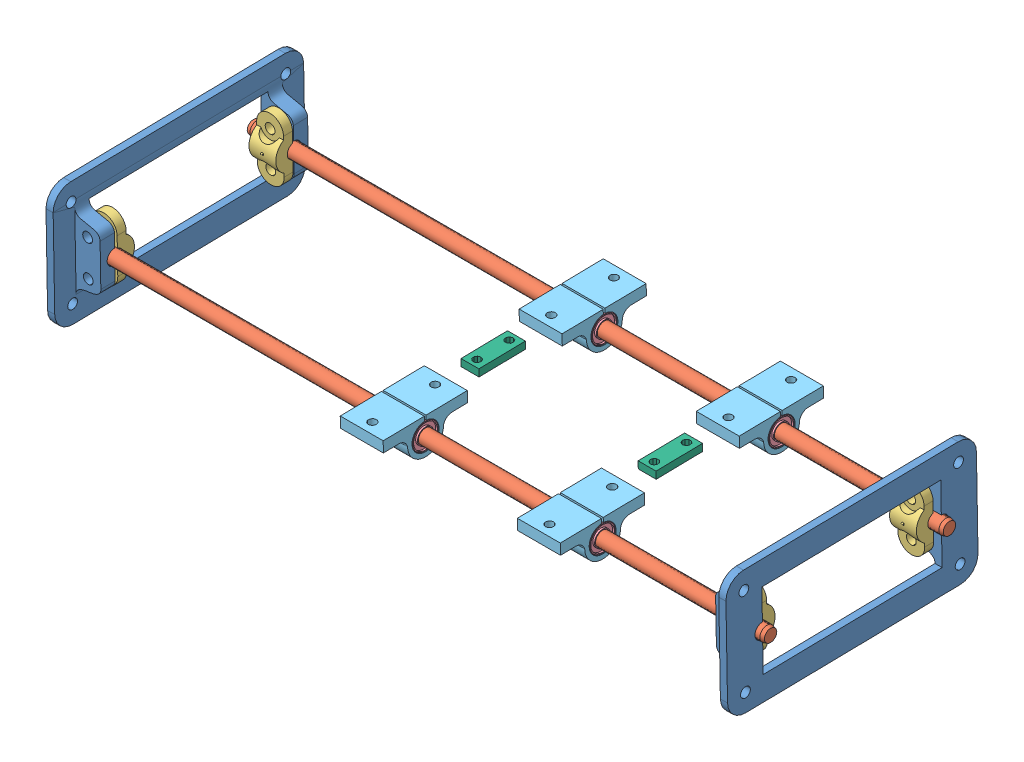
SolidWorks assembly MS1 - SubAssembly B - Yaxis, configuration Default. Lengths in mm.
Overall size (389 72.16 147.33).
18 component instances, 6 part files, 45 mates.
Components (placement in the parent):
- Y Rod Mount-1: Y Rod Mount [Default] at (380 175.2275 237.1388) x (-1 0 0) z (0 0.017689 -0.999844) size (18.11 69.69 140)
- Y Rod Mount-2: Y Rod Mount [Default] at (0 172.751 377.1169) x (1 0 0) z (0 -0.017689 0.999844) size (18.11 69.69 140)
- Steel Rod-3: Steel Rod [Default] at (190 173.1048 357.12) size (389 8 8)
- Steel Rod-4: Steel Rod [Default] at (190 174.8737 257.1356) size (389 8 8)
- Z Rod Clamp-1: Z Rod Clamp [Default] at (369 174.856 258.1355) x (0 0.999844 0.017689) z (1 0 0) size (35 10 15)
- Z Rod Clamp-2: Z Rod Clamp [Default] at (11 174.856 258.1355) x (0 0.999844 0.017689) z (1 0 0) size (35 10 15)
- Z Rod Clamp-3: Z Rod Clamp [Default] at (11 173.1225 356.1202) x (0 -0.999844 -0.017689) z (1 0 0) size (35 10 15)
- Z Rod Clamp-4: Z Rod Clamp [Default] at (369 173.1225 356.1202) x (0 -0.999844 -0.017689) z (1 0 0) size (35 10 15)
- LM8UU Bearing-1: LM8UU Bearing [Default] at (278.6557 173.1048 357.12) size (24 15 15)
- LM8UU Bearing-2: LM8UU Bearing [Default] at (179.6557 173.1048 357.12) size (24 15 15)
- LM8UU Bearing-3: LM8UU Bearing [Default] at (278.6557 174.8737 257.1356) x (1 0 0) z (0 0.453084 0.891468) size (24 15 15)
- LM8UU Bearing-4: LM8UU Bearing [Default] at (179.6557 174.8737 257.1356) size (24 15 15)
- LM8UU Bearing Holder-1: LM8UU Bearing Holder [Default] at (266.6557 183.542 333.7824) x (0 -0.017689 0.999844) z (0 0.999844 0.017689) size (47 24 20.05)
- LM8UU Bearing Holder-2: LM8UU Bearing Holder [Default] at (167.6557 183.542 333.7824) x (0 -0.017689 0.999844) z (0 0.999844 0.017689) size (47 24 20.05)
- LM8UU Bearing Holder-3: LM8UU Bearing Holder [Default] at (266.6557 185.3109 233.798) x (0 -0.017689 0.999844) z (0 0.999844 0.017689) size (47 24 20.05)
- LM8UU Bearing Holder-4: LM8UU Bearing Holder [Default] at (167.6557 185.3109 233.798) x (0 -0.017689 0.999844) z (0 0.999844 0.017689) size (47 24 20.05)
- Y Belt Clamp-1: Y Belt Clamp [Default] at (273.6557 180.2413 294.2178) x (0 -0.017689 0.999844) z (0 0.999844 0.017689) size (26 10 4)
- Y Belt Clamp-2: Y Belt Clamp [Default] at (174.6557 183.7808 320.2845) x (0 0.017689 -0.999844) z (0 -0.999844 -0.017689) size (26 10 4)
Mates (geometry in assembly coordinates):
- Coincident1: coincident anti-aligned: plane of Y Rod Mount-2 through (0 210.0682 237.7552) normal (-1 0 0); plane of assembly through (0 0 0) normal (1 0 0)
- Coincident2: coincident aligned: plane of Y Rod Mount-1 through (380 207.5917 377.7333) normal (1 0 0); plane of assembly through (380 0 0) normal (1 0 0)
- Distance1: distance = 0 mm aligned: plane of Y Rod Mount-2 through (11.0136 156.2553 376.825) normal (0 -0.017689 0.999844); plane of Y Rod Mount-1 through (368.9864 156.2553 376.825) normal (0 -0.017689 0.999844)
- Distance2: distance = 0 mm aligned: plane of Y Rod Mount-2 through (0 210.0682 237.7552) normal (0 0.999844 0.017689); plane of Y Rod Mount-1 through (380 207.5917 377.7333) normal (0 0.999844 0.017689)
- Concentric3: concentric aligned: cylinder of Y Rod Mount-2 through (18.1149 174.8737 257.1356) axis (-1 0 0) radius 4.2788; cylinder of Steel Rod-4 through (384.5 174.8737 257.1356) axis (-1 0 0) radius 4
- Concentric4: concentric aligned: cylinder of Y Rod Mount-2 through (18.1149 173.1048 357.12) axis (-1 0 0) radius 4.2788; cylinder of Steel Rod-3 through (384.5 173.1048 357.12) axis (-1 0 0) radius 4
- Distance3: distance = 4.5 mm aligned: plane of Steel Rod-3 through (-4.5 173.1048 357.12) normal (-1 0 0); plane of Y Rod Mount-2 through (0 210.0682 237.7552) normal (-1 0 0)
- Distance4: distance = 4.5 mm aligned: plane of Steel Rod-4 through (-4.5 174.8737 257.1356) normal (-1 0 0); plane of Y Rod Mount-2 through (0 210.0682 237.7552) normal (-1 0 0)
- Concentric5: concentric anti-aligned: cylinder of Steel Rod-4 through (384.5 174.8737 257.1356) axis (-1 0 0) radius 4; cylinder of Z Rod Clamp-1 through (361.5 174.8737 257.1356) axis (1 0 0) radius 4.1
- Concentric6: concentric anti-aligned: cylinder of Steel Rod-4 through (384.5 174.8737 257.1356) axis (-1 0 0) radius 4; cylinder of Z Rod Clamp-2 through (3.5 174.8737 257.1356) axis (1 0 0) radius 4.1
- Concentric7: concentric anti-aligned: cylinder of Steel Rod-3 through (384.5 173.1048 357.12) axis (-1 0 0) radius 4; cylinder of Z Rod Clamp-3 through (3.5 173.1048 357.12) axis (1 0 0) radius 4.1
- Concentric8: concentric anti-aligned: cylinder of Steel Rod-3 through (384.5 173.1048 357.12) axis (-1 0 0) radius 4; cylinder of Z Rod Clamp-4 through (361.5 173.1048 357.12) axis (1 0 0) radius 4.1
- Parallel2: parallel anti-aligned: plane of Y Rod Mount-2 through (18.1149 173.1048 357.12) normal (0 0.017689 -0.999844); plane of Z Rod Clamp-3 through (11 173.1225 356.1202) normal (0 -0.017689 0.999844)
- Distance6: distance = 0.5 mm aligned: plane of Y Rod Mount-2 through (18 186.992 237.3469) normal (1 0 0); plane of Z Rod Clamp-3 through (18.5 173.2905 346.6217) normal (1 0 0)
- Parallel5: parallel anti-aligned: plane of Y Rod Mount-2 through (18.1149 174.8737 257.1356) normal (0 -0.017689 0.999844); plane of Z Rod Clamp-2 through (11 174.856 258.1355) normal (0 0.017689 -0.999844)
- Distance7: distance = 0.5 mm aligned: plane of Z Rod Clamp-2 through (18.5 174.688 267.634) normal (1 0 0); plane of Y Rod Mount-2 through (18 186.992 237.3469) normal (1 0 0)
- Parallel6: parallel anti-aligned: plane of Y Rod Mount-1 through (361.8851 174.8737 257.1356) normal (0 -0.017689 0.999844); plane of Z Rod Clamp-1 through (369 174.856 258.1355) normal (0 0.017689 -0.999844)
- Distance9: distance = 0.5 mm aligned: plane of Z Rod Clamp-1 through (361.5 174.688 267.634) normal (-1 0 0); plane of Y Rod Mount-1 through (362 184.5155 377.325) normal (-1 0 0)
- Parallel7: parallel anti-aligned: plane of Y Rod Mount-1 through (361.8851 173.1048 357.12) normal (0 0.017689 -0.999844); plane of Z Rod Clamp-4 through (369 173.1225 356.1202) normal (0 -0.017689 0.999844)
- Distance10: distance = 0.5 mm aligned: plane of Z Rod Clamp-4 through (361.5 173.2905 346.6217) normal (-1 0 0); plane of Y Rod Mount-1 through (362 184.5155 377.325) normal (-1 0 0)
- Concentric11: concentric anti-aligned: cylinder of Steel Rod-4 through (384.5 174.8737 257.1356) axis (-1 0 0) radius 4; cylinder of LM8UU Bearing Holder-4 through (167.6557 174.8737 257.1356) axis (1 0 0) radius 7.55
- Parallel8: parallel aligned: plane of Y Rod Mount-2 through (0 210.0682 237.7552) normal (0 0.999844 0.017689); plane of LM8UU Bearing Holder-4 through (167.6557 185.3109 233.798) normal (0 0.999844 0.017689)
- Concentric12: concentric aligned: cylinder of Steel Rod-4 through (384.5 174.8737 257.1356) axis (-1 0 0) radius 4; cylinder of LM8UU Bearing-4 through (133.9662 174.8737 257.1356) axis (-1 0 0) radius 4
- Coincident18: coincident aligned: plane of LM8UU Bearing-4 through (191.6557 174.8737 257.1356) normal (1 0 0); plane of LM8UU Bearing Holder-4 through (191.6557 173.5638 272.0962) normal (1 0 0)
- Concentric13: concentric aligned: cylinder of Steel Rod-4 through (384.5 174.8737 257.1356) axis (-1 0 0) radius 4; cylinder of LM8UU Bearing-3 through (232.9662 174.8737 257.1356) axis (-1 0 0) radius 4
- Concentric14: concentric anti-aligned: cylinder of LM8UU Bearing-3 through (232.9662 174.8737 257.1356) axis (-1 0 0) radius 7.5; cylinder of LM8UU Bearing Holder-3 through (266.6557 174.8737 257.1356) axis (1 0 0) radius 7.55
- Coincident19: coincident aligned: plane of LM8UU Bearing Holder-3 through (266.6557 185.3109 233.798) normal (0 0.999844 0.017689); plane of LM8UU Bearing Holder-4 through (167.6557 185.3109 233.798) normal (0 0.999844 0.017689)
- Coincident20: coincident aligned: plane of LM8UU Bearing-3 through (290.6557 174.8737 257.1356) normal (1 0 0); plane of LM8UU Bearing Holder-3 through (290.6557 173.5638 272.0962) normal (1 0 0)
- Concentric15: concentric aligned: cylinder of Steel Rod-3 through (384.5 173.1048 357.12) axis (-1 0 0) radius 4; cylinder of LM8UU Bearing-2 through (133.9662 173.1048 357.12) axis (-1 0 0) radius 4
- Concentric16: concentric anti-aligned: cylinder of LM8UU Bearing-2 through (133.9662 173.1048 357.12) axis (-1 0 0) radius 7.5; cylinder of LM8UU Bearing Holder-2 through (167.6557 173.1048 357.12) axis (1 0 0) radius 7.55
- Coincident21: coincident aligned: plane of LM8UU Bearing Holder-2 through (167.6557 183.542 333.7824) normal (0 0.999844 0.017689); plane of LM8UU Bearing Holder-4 through (167.6557 185.3109 233.798) normal (0 0.999844 0.017689)
- Coincident22: coincident aligned: plane of LM8UU Bearing-2 through (191.6557 173.1048 357.12) normal (1 0 0); plane of LM8UU Bearing Holder-2 through (191.6557 171.7949 372.0806) normal (1 0 0)
- Concentric17: concentric aligned: cylinder of Steel Rod-3 through (384.5 173.1048 357.12) axis (-1 0 0) radius 4; cylinder of LM8UU Bearing-1 through (232.9662 173.1048 357.12) axis (-1 0 0) radius 4
- Concentric18: concentric anti-aligned: cylinder of LM8UU Bearing-1 through (232.9662 173.1048 357.12) axis (-1 0 0) radius 7.5; cylinder of LM8UU Bearing Holder-1 through (266.6557 173.1048 357.12) axis (1 0 0) radius 7.55
- Coincident23: coincident aligned: plane of LM8UU Bearing Holder-1 through (266.6557 183.542 333.7824) normal (0 0.999844 0.017689); plane of LM8UU Bearing Holder-2 through (167.6557 183.542 333.7824) normal (0 0.999844 0.017689)
- Coincident24: coincident aligned: plane of LM8UU Bearing-1 through (290.6557 173.1048 357.12) normal (1 0 0); plane of LM8UU Bearing Holder-1 through (290.6557 171.7949 372.0806) normal (1 0 0)
- Coincident25: coincident aligned: plane of LM8UU Bearing Holder-1 through (290.6557 171.7949 372.0806) normal (1 0 0); plane of LM8UU Bearing Holder-3 through (290.6557 173.5638 272.0962) normal (1 0 0)
- Coincident26: coincident aligned: plane of LM8UU Bearing Holder-2 through (191.6557 171.7949 372.0806) normal (1 0 0); plane of LM8UU Bearing Holder-4 through (191.6557 173.5638 272.0962) normal (1 0 0)
- Distance11: distance = 75 mm anti-aligned: plane of LM8UU Bearing Holder-2 through (191.6557 171.7949 372.0806) normal (1 0 0); plane of LM8UU Bearing Holder-1 through (266.6557 171.7949 372.0806) normal (-1 0 0)
- Coincident28: coincident aligned: plane of LM8UU Bearing Holder-1 through (266.6557 183.542 333.7824) normal (0 0.999844 0.017689); plane of Y Belt Clamp-1 through (273.6557 184.2407 294.2885) normal (0 0.999844 0.017689)
- Distance14: distance = 13.5 mm anti-aligned: plane of LM8UU Bearing Holder-1 through (266.6557 177.5429 333.6762) normal (0 0.017689 -0.999844); plane of Y Belt Clamp-1 through (283.6557 183.7808 320.2845) normal (0 -0.017689 0.999844)
- Distance15: distance = 7 mm aligned: plane of LM8UU Bearing Holder-3 through (290.6557 173.5638 272.0962) normal (1 0 0); plane of Y Belt Clamp-1 through (283.6557 184.2407 294.2885) normal (1 0 0)
- Coincident31: coincident aligned: plane of LM8UU Bearing Holder-2 through (167.6557 183.542 333.7824) normal (0 0.999844 0.017689); plane of Y Belt Clamp-2 through (174.6557 183.7808 320.2845) normal (0 0.999844 0.017689)
- Distance13: distance = 13.5 mm anti-aligned: plane of LM8UU Bearing Holder-2 through (167.6557 177.5429 333.6762) normal (0 0.017689 -0.999844); plane of Y Belt Clamp-2 through (184.6557 179.7814 320.2137) normal (0 -0.017689 0.999844)
- Distance12: distance = 7 mm aligned: plane of LM8UU Bearing Holder-2 through (191.6557 171.7949 372.0806) normal (1 0 0); plane of Y Belt Clamp-2 through (184.6557 179.7814 320.2137) normal (1 0 0)
